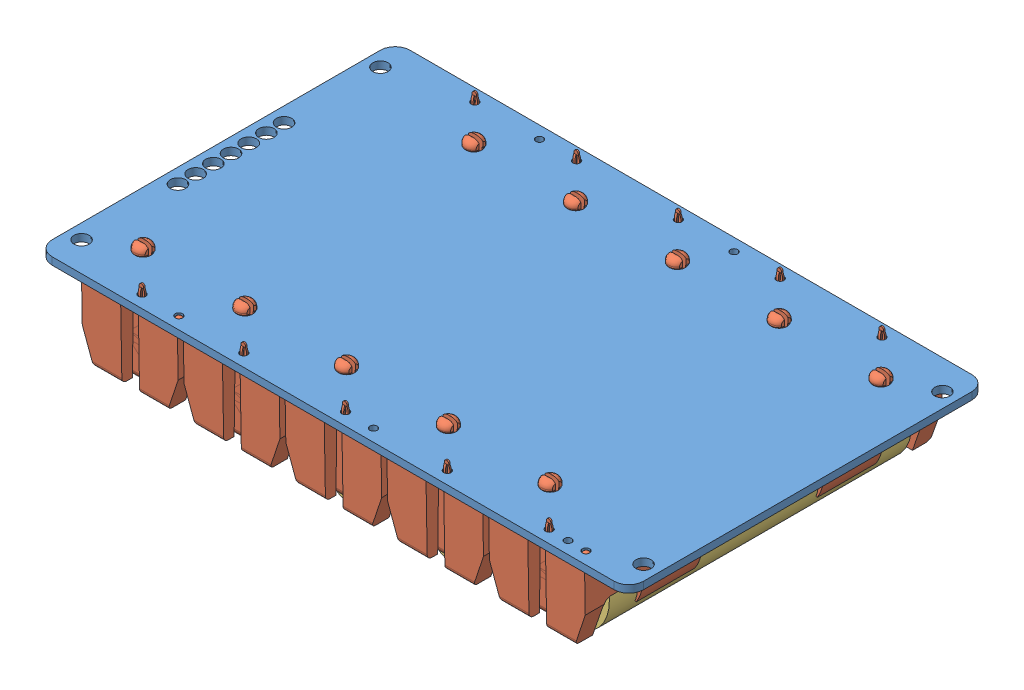
SolidWorks assembly PCB_Battery Assembly, configuration Default. Lengths in mm.
Overall size (127.38 21.9 77.22).
16 component instances, 3 part files, 15 mates.
Components (placement in the parent):
- Battery PCB-1: Battery PCB [Default] at (-148.3186 115.135 -16.9005) x (1 0 0) z (0 -1 0) size (127.38 77.06 1.59)
- Battery Assembly-1: Battery Assembly [Default] at (-101.6605 145.5711 -35.2548) x (-1 0 0) z (0 0 1) size (20.65 21.9 77.14)
  - Battery Holder - keystone-PN1043-1: Battery Holder - keystone-PN1043 [Default] at (27.979 42.1729 59.6018) size (20.65 18.93 77.14)
  - battery_6612-1: battery_6612 [Default] at (36.333 41.1675 88.8909) x (1 0 0) z (0 1 0) size (18.3 65.05 18.3)
- Battery Assembly-2: Battery Assembly [Default] at (-130.4862 145.5711 78.5174) x (1 0 0) z (0 0 -1) size (20.65 21.9 77.14)
  - Battery Holder - keystone-PN1043-1: Battery Holder - keystone-PN1043 [Default] at (27.979 42.1729 59.6018) size (20.65 18.93 77.14)
  - battery_6612-1: battery_6612 [Default] at (36.333 41.1675 88.8909) x (1 0 0) z (0 1 0) size (18.3 65.05 18.3)
- Battery Assembly-3: Battery Assembly [Default] at (-13.9797 145.5711 -35.2548) x (-1 0 0) z (0 0 1) size (20.65 21.9 77.14)
  - Battery Holder - keystone-PN1043-1: Battery Holder - keystone-PN1043 [Default] at (27.979 42.1729 59.6018) size (20.65 18.93 77.14)
  - battery_6612-1: battery_6612 [Default] at (36.333 41.1675 88.8909) x (1 0 0) z (0 1 0) size (18.3 65.05 18.3)
- Battery Assembly-4: Battery Assembly [Default] at (-108.566 145.5711 78.5174) x (1 0 0) z (0 0 -1) size (20.65 21.9 77.14)
  - Battery Holder - keystone-PN1043-1: Battery Holder - keystone-PN1043 [Default] at (27.979 42.1729 59.6018) size (20.65 18.93 77.14)
  - battery_6612-1: battery_6612 [Default] at (36.333 41.1675 88.8909) x (1 0 0) z (0 1 0) size (18.3 65.05 18.3)
- Battery Assembly-5: Battery Assembly [Default] at (-79.7403 145.5711 -35.2548) x (-1 0 0) z (0 0 1) size (20.65 21.9 77.14)
  - Battery Holder - keystone-PN1043-1: Battery Holder - keystone-PN1043 [Default] at (27.979 42.1729 59.6018) size (20.65 18.93 77.14)
  - battery_6612-1: battery_6612 [Default] at (36.333 41.1675 88.8909) x (1 0 0) z (0 1 0) size (18.3 65.05 18.3)
Mates (geometry in assembly coordinates):
- Coincident3: coincident aligned: plane of Battery PCB-1 through (-148.3186 113.5475 -16.9005) normal (0 -1 0); plane of Battery Assembly-3/Battery Holder - keystone-PN1043-1 through (-39.9876 113.5475 56.0737) normal (0 -1 0)
- Concentric5: concentric anti-aligned: cylinder of Battery PCB-1 through (-42.3117 113.5475 -5.9912) axis (0 1 0) radius 1.7145; cylinder of Battery Assembly-3/Battery Holder - keystone-PN1043-1 through (-42.3117 113.5475 -5.9912) axis (0 -1 0) radius 1.4605
- Concentric6: concentric anti-aligned: cylinder of Battery PCB-1 through (-58.3137 113.5475 49.2538) axis (0 1 0) radius 1.7145; cylinder of Battery Assembly-3/Battery Holder - keystone-PN1043-1 through (-58.3137 113.5475 49.2538) axis (0 -1 0) radius 1.4605
- Coincident4: coincident aligned: plane of Battery PCB-1 through (-148.3186 113.5475 -16.9005) normal (0 -1 0); plane of Battery Assembly-4/Battery Holder - keystone-PN1043-1 through (-82.558 113.5475 -12.8111) normal (0 -1 0)
- Coincident5: coincident aligned: plane of Battery PCB-1 through (-148.3186 113.5475 -16.9005) normal (0 -1 0); plane of Battery Assembly-2/Battery Holder - keystone-PN1043-1 through (-104.4782 113.5475 -12.8111) normal (0 -1 0)
- Concentric9: concentric anti-aligned: cylinder of Battery PCB-1 through (-64.2319 113.5475 -5.9912) axis (0 1 0) radius 1.7145; cylinder of Battery Assembly-4/Battery Holder - keystone-PN1043-1 through (-64.2319 113.5475 -5.9912) axis (0 -1 0) radius 1.4605
- Concentric10: concentric anti-aligned: cylinder of Battery PCB-1 through (-80.2339 113.5475 49.2538) axis (0 1 0) radius 1.7145; cylinder of Battery Assembly-4/Battery Holder - keystone-PN1043-1 through (-80.2339 113.5475 49.2538) axis (0 -1 0) radius 1.4605
- Concentric11: concentric anti-aligned: cylinder of Battery PCB-1 through (-102.1541 113.5475 49.2538) axis (0 1 0) radius 1.7145; cylinder of Battery Assembly-2/Battery Holder - keystone-PN1043-1 through (-102.1541 113.5475 49.2538) axis (0 -1 0) radius 1.4605
- Concentric12: concentric anti-aligned: cylinder of Battery PCB-1 through (-86.1521 113.5475 -5.9912) axis (0 1 0) radius 1.7145; cylinder of Battery Assembly-2/Battery Holder - keystone-PN1043-1 through (-86.1521 113.5475 -5.9912) axis (0 -1 0) radius 1.4605
- Coincident6: coincident aligned: plane of Battery PCB-1 through (-148.3186 113.5475 -16.9005) normal (0 -1 0); plane of Battery Assembly-5/Battery Holder - keystone-PN1043-1 through (-105.7482 113.5475 56.0737) normal (0 -1 0)
- Concentric13: concentric aligned: circle of Battery PCB-1; cylinder of Battery Assembly-5/Battery Holder - keystone-PN1043-1 through (-124.0743 113.5475 49.2538) axis (0 -1 0) radius 1.4605
- Concentric14: concentric anti-aligned: cylinder of Battery PCB-1 through (-108.0723 113.5475 -5.9912) axis (0 1 0) radius 1.7145; cylinder of Battery Assembly-5/Battery Holder - keystone-PN1043-1 through (-108.0723 113.5475 -5.9912) axis (0 -1 0) radius 1.4605
- Coincident7: coincident aligned: plane of Battery PCB-1 through (-148.3186 113.5475 -16.9005) normal (0 -1 0); plane of Battery Assembly-1/Battery Holder - keystone-PN1043-1 through (-127.6684 113.5475 56.0737) normal (0 -1 0)
- Concentric15: concentric anti-aligned: cylinder of Battery PCB-1 through (-145.9945 113.5475 49.2538) axis (0 1 0) radius 1.7145; cylinder of Battery Assembly-1/Battery Holder - keystone-PN1043-1 through (-145.9945 113.5475 49.2538) axis (0 -1 0) radius 1.4605
- Concentric16: concentric anti-aligned: cylinder of Battery PCB-1 through (-129.9925 113.5475 -5.9912) axis (0 1 0) radius 1.7145; cylinder of Battery Assembly-1/Battery Holder - keystone-PN1043-1 through (-129.9925 113.5475 -5.9912) axis (0 -1 0) radius 1.4605
